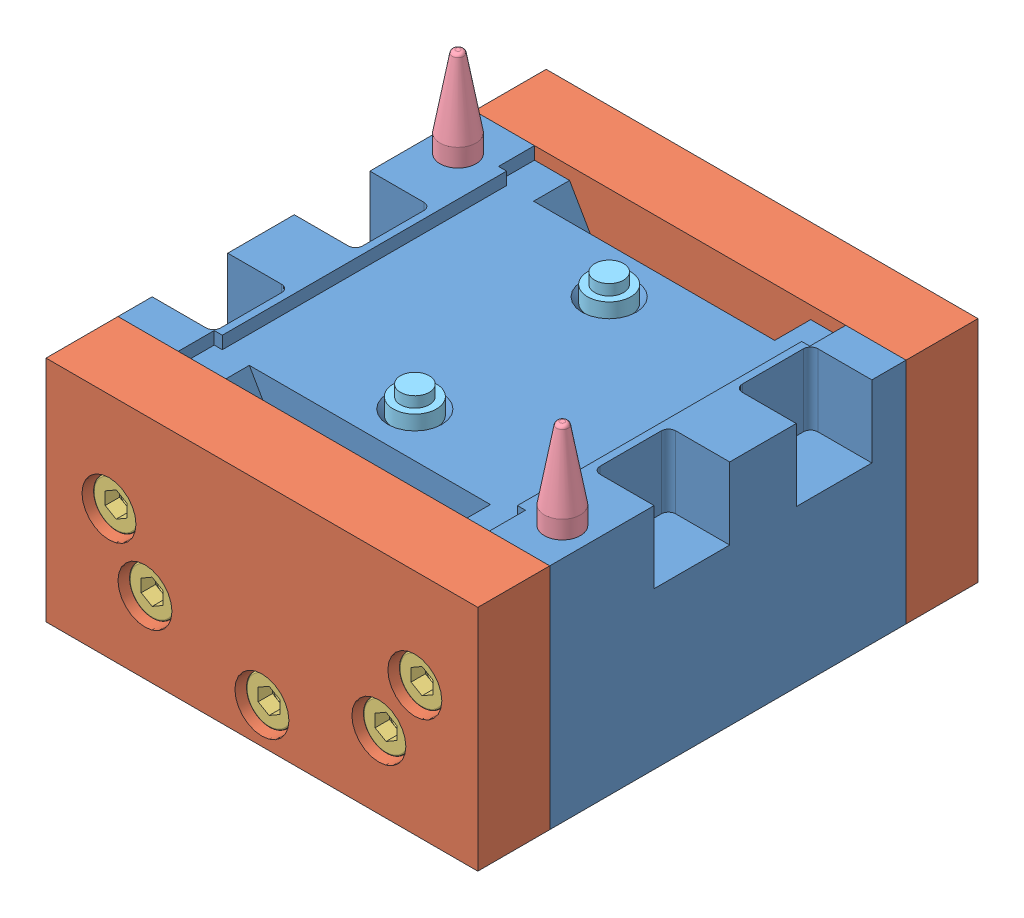
SolidWorks assembly  ЧМВ1.01.00 - Сборка Матрицы, configuration По умолчанию. Lengths in mm.
Overall size (120 88.5 139).
19 component instances, 5 part files, 32 mates.
Components (placement in the parent):
- ЧМВ1.01.02 - Матрица-1: ЧМВ1.01.02 - Матрица [Default] at origin size (120 63.5 99)
- ЧМВ1.01.02 - Боковина Пресс-формы-1: ЧМВ1.01.02 - Боковина Пресс-формы [По умолчанию] at (0 36.1757 49.5) size (120 63.5 20)
- ЧМВ1.01.02 - Боковина Пресс-формы-3: ЧМВ1.01.02 - Боковина Пресс-формы [По умолчанию] at (0 36.1757 -49.5) x (-1 0 0) z (0 0 -1) size (120 63.5 20)
- socket head cap screw_iso-1: socket head cap screw_iso [ISO 4762 M8 x 16 - 16N] at (-42.5 36 -67.5) x (0 0 1) z (-1 0 0) size (24 13 13)
- socket head cap screw_iso-2: socket head cap screw_iso [ISO 4762 M8 x 16 - 16N] at (-32.5 20 -67.5) x (0 0 1) z (-1 0 0) size (24 13 13)
- socket head cap screw_iso-3: socket head cap screw_iso [ISO 4762 M8 x 16 - 16N] at (0 10 -67.5) x (0 0 1) z (-1 0 0) size (24 13 13)
- socket head cap screw_iso-4: socket head cap screw_iso [ISO 4762 M8 x 16 - 16N] at (32.5 20 -67.5) x (0 0 1) z (-1 0 0) size (24 13 13)
- socket head cap screw_iso-5: socket head cap screw_iso [ISO 4762 M8 x 16 - 16N] at (42.5 36 -67.5) x (0 0 1) z (-1 0 0) size (24 13 13)
- socket head cap screw_iso-6: socket head cap screw_iso [ISO 4762 M8 x 16 - 16N] at (42.5 36 67.5) x (0 0 -1) z (1 0 0) size (24 13 13)
- socket head cap screw_iso-7: socket head cap screw_iso [ISO 4762 M8 x 16 - 16N] at (32.5 20 67.5) x (0 0 -1) z (1 0 0) size (24 13 13)
- socket head cap screw_iso-10: socket head cap screw_iso [ISO 4762 M8 x 16 - 16N] at (-42.5 36 67.5) x (0 0 -1) z (1 0 0) size (24 13 13)
- socket head cap screw_iso-8: socket head cap screw_iso [ISO 4762 M8 x 16 - 16N] at (0 10 67.5) x (0 0 -1) z (1 0 0) size (24 13 13)
- socket head cap screw_iso-9: socket head cap screw_iso [ISO 4762 M8 x 16 - 16N] at (-32.5 20 67.5) x (0 0 -1) z (1 0 0) size (24 13 13)
- socket head cap screw_iso-11: socket head cap screw_iso [ISO 4762 M8 x 16 - 16N] at (-32.5 20 67.5) x (0 0 -1) z (1 0 0) size (24 13 13)
- socket head cap screw_iso-12: socket head cap screw_iso [ISO 4762 M8 x 16 - 16N] at (-42.5 36 67.5) x (0 0 -1) z (1 0 0) size (24 13 13)
- ЧМВ1.01.03 - Направляющая-1: ЧМВ1.01.03 - Направляющая [Default] at (52 33.5 38) x (0 1 0) z (-0.458497 0 -0.888696) size (55 10 10)
- ЧМВ1.01.03 - Направляющая-3: ЧМВ1.01.03 - Направляющая [Default] at (-51.997 33.5 -37) x (0 1 0) z (-0.61776 0 -0.786366) size (55 10 10)
- ЧМВ1.01.04 - Подставка-2: ЧМВ1.01.04 - Подставка [По умолчанию] at (0 48 -27) x (0.955678 0 -0.294415) z (0 -1 0) size (12 12 36)
- ЧМВ1.01.04 - Подставка-3: ЧМВ1.01.04 - Подставка [По умолчанию] at (0 48 27) x (0.972927 0 -0.231111) z (0 -1 0) size (12 12 36)
Mates (geometry in assembly coordinates):
- Совпадение1: coincident anti-aligned: plane of ЧМВ1.01.02 - Матрица-1 through (60 63.5 49.5) normal (0 0 1); plane of Боковина Пресс-формы.-1 through (0 36.1757 49.5) normal (0 0 -1)
- Концентричный1: concentric anti-aligned: cylinder of ЧМВ1.01.02 - Матрица-1 through (42.5 36 49.5) axis (0 0 1) radius 3.5; cylinder of Боковина Пресс-формы.-1 through (42.5 36 69.5) axis (0 0 -1) radius 4.25
- Концентричный2: concentric anti-aligned: cylinder of ЧМВ1.01.02 - Матрица-1 through (-42.5 36 49.5) axis (0 0 1) radius 3.5; cylinder of Боковина Пресс-формы.-1 through (-42.5 36 69.5) axis (0 0 -1) radius 4.25
- Совпадение3: coincident anti-aligned: plane of ЧМВ1.01.02 - Матрица-1 through (60 63.5 -49.5) normal (0 0 -1); plane of Боковина Пресс-формы.-3 through (0 36.1757 -49.5) normal (0 0 1)
- Концентричный5: concentric anti-aligned: cylinder of Боковина Пресс-формы.-3 through (-42.5 36 -69.5) axis (0 0 1) radius 4.25; cylinder of socket head cap screw_iso-1 through (-42.5 36 -99.25) axis (0 0 -1) radius 6.5
- Совпадение4: coincident anti-aligned: plane of Боковина Пресс-формы.-3 through (-42.5 36 -59.5) normal (0 0 -1); plane of socket head cap screw_iso-1 through (-42.5 42.5 -59.5) normal (0 0 1)
- Концентричный6: concentric aligned: cylinder of Боковина Пресс-формы.-3 through (-32.5 20 -59.5) axis (0 0 -1) radius 7.5; cylinder of socket head cap screw_iso-2 through (-32.5 20 -99.25) axis (0 0 -1) radius 6.5
- Совпадение5: coincident anti-aligned: plane of Боковина Пресс-формы.-3 through (-32.5 20 -59.5) normal (0 0 -1); plane of socket head cap screw_iso-2 through (-32.5 26.5 -59.5) normal (0 0 1)
- Концентричный7: concentric anti-aligned: cylinder of Боковина Пресс-формы.-3 through (0 10 -69.5) axis (0 0 1) radius 4.25; cylinder of socket head cap screw_iso-3 through (0 10 -99.25) axis (0 0 -1) radius 6.5
- Совпадение6: coincident anti-aligned: plane of Боковина Пресс-формы.-3 through (0 10 -59.5) normal (0 0 -1); plane of socket head cap screw_iso-3 through (0 16.5 -59.5) normal (0 0 1)
- Концентричный8: concentric anti-aligned: cylinder of Боковина Пресс-формы.-3 through (32.5 20 -69.5) axis (0 0 1) radius 4.25; cylinder of socket head cap screw_iso-4 through (32.5 20 -99.25) axis (0 0 -1) radius 6.5
- Совпадение7: coincident anti-aligned: plane of Боковина Пресс-формы.-3 through (32.5 20 -59.5) normal (0 0 -1); plane of socket head cap screw_iso-4 through (32.5 26.5 -59.5) normal (0 0 1)
- Концентричный9: concentric aligned: cylinder of Боковина Пресс-формы.-3 through (42.5 36 -59.5) axis (0 0 -1) radius 7.5; cylinder of socket head cap screw_iso-5 through (42.5 36 -99.25) axis (0 0 -1) radius 6.5
- Совпадение8: coincident anti-aligned: plane of Боковина Пресс-формы.-3 through (42.5 36 -59.5) normal (0 0 -1); plane of socket head cap screw_iso-5 through (42.5 42.5 -59.5) normal (0 0 1)
- Концентричный10: concentric anti-aligned: cylinder of Боковина Пресс-формы.-1 through (42.5 36 69.5) axis (0 0 -1) radius 4.25; cylinder of socket head cap screw_iso-6 through (42.5 36 99.25) axis (0 0 1) radius 6.5
- Совпадение9: coincident anti-aligned: plane of Боковина Пресс-формы.-1 through (42.5 36 59.5) normal (0 0 1); plane of socket head cap screw_iso-6 through (42.5 42.5 59.5) normal (0 0 -1)
- Концентричный11: concentric aligned: cylinder of Боковина Пресс-формы.-1 through (32.5 20 59.5) axis (0 0 1) radius 7.5; cylinder of socket head cap screw_iso-7 through (32.5 20 99.25) axis (0 0 1) radius 6.5
- Совпадение10: coincident anti-aligned: plane of Боковина Пресс-формы.-1 through (32.5 20 59.5) normal (0 0 1); plane of socket head cap screw_iso-7 through (32.5 26.5 59.5) normal (0 0 -1)
- Концентричный12: concentric anti-aligned: cylinder of Боковина Пресс-формы.-1 through (0 10 69.5) axis (0 0 -1) radius 4.25; cylinder of socket head cap screw_iso-8 through (0 10 99.25) axis (0 0 1) radius 6.5
- Совпадение11: coincident anti-aligned: plane of Боковина Пресс-формы.-1 through (0 10 59.5) normal (0 0 1); plane of socket head cap screw_iso-8 through (0 16.5 59.5) normal (0 0 -1)
- Концентричный13: concentric aligned: cylinder of Боковина Пресс-формы.-1 through (-32.5 20 59.5) axis (0 0 1) radius 7.5; cylinder of socket head cap screw_iso-9 through (-32.5 20 99.25) axis (0 0 1) radius 6.5
- Совпадение12: coincident anti-aligned: plane of Боковина Пресс-формы.-1 through (-32.5 20 59.5) normal (0 0 1); plane of socket head cap screw_iso-9 through (-32.5 26.5 59.5) normal (0 0 -1)
- Концентричный14: concentric aligned: cylinder of Боковина Пресс-формы.-1 through (-42.5 36 59.5) axis (0 0 1) radius 7.5; cylinder of socket head cap screw_iso-10 through (-42.5 36 99.25) axis (0 0 1) radius 6.5
- Совпадение13: coincident anti-aligned: plane of Боковина Пресс-формы.-1 through (-42.5 36 59.5) normal (0 0 1); plane of socket head cap screw_iso-10 through (-42.5 42.5 59.5) normal (0 0 -1)
- Концентричный15: concentric anti-aligned: cylinder of ЧМВ1.01.02 - Матрица-1 through (52 33.5 38) axis (0 1 0) radius 5; cylinder of Направляющая-1 through (52 33.5 38) axis (0 -1 0) radius 5
- Совпадение14: coincident anti-aligned: plane of ЧМВ1.01.02 - Матрица-1 through (52 33.5 38) normal (0 1 0); circle of Направляющая-1
- Концентричный17: concentric anti-aligned: cylinder of ЧМВ1.01.02 - Матрица-1 through (-51.997 33.5 -37) axis (0 1 0) radius 5; cylinder of Направляющая-3 through (-51.997 33.5 -37) axis (0 -1 0) radius 5
- Совпадение17: coincident anti-aligned: plane of ЧМВ1.01.02 - Матрица-1 through (-51.997 33.5 -37) normal (0 1 0); circle of Направляющая-3
- Концентричный20: concentric anti-aligned: cylinder of ЧМВ1.01.02 - Матрица-1 through (0 30 -27) axis (0 1 0) radius 6; cylinder of Подставка-2 through (0 30 -27) axis (0 -1 0) radius 6
- Концентричный21: concentric anti-aligned: cylinder of ЧМВ1.01.02 - Матрица-1 through (0 30 27) axis (0 1 0) radius 6; cylinder of Подставка-3 through (0 30 27) axis (0 -1 0) radius 6
- Совпадение20: coincident anti-aligned: plane of ЧМВ1.01.02 - Матрица-1 through (0 30 0) normal (0 1 0); plane of Подставка-3 through (0 30 27) normal (0 -1 0)
- Совпадение21: coincident anti-aligned: plane of ЧМВ1.01.02 - Матрица-1 through (0 30 0) normal (0 1 0); plane of Подставка-2 through (0 30 -27) normal (0 -1 0)
